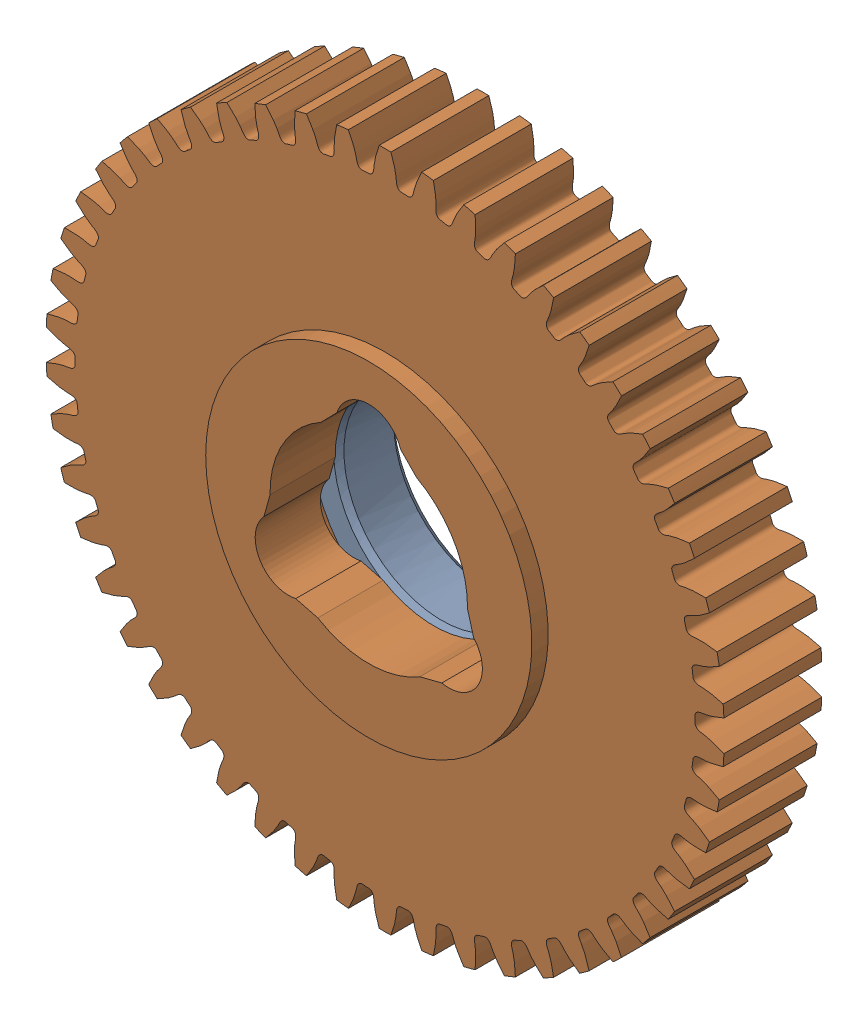
SolidWorks assembly 217-3219-101 Rev1, configuration Default. Lengths in mm.
Overall size (66.33 66.39 12.7).
2 component instances, 2 part files, 0 mates.
Components (placement in the parent):
- 217-2428-022 Rev1-1: 217-2428-022 Rev1 [Default] at (7.6012 15.863 22.905) size (28.57 28.57 6.1)
- 217-3219-001 Rev1_50t-1: 217-3219-001 Rev1_50t [Default] at (7.6012 15.863 26.207) size (66.33 66.39 11.11)
